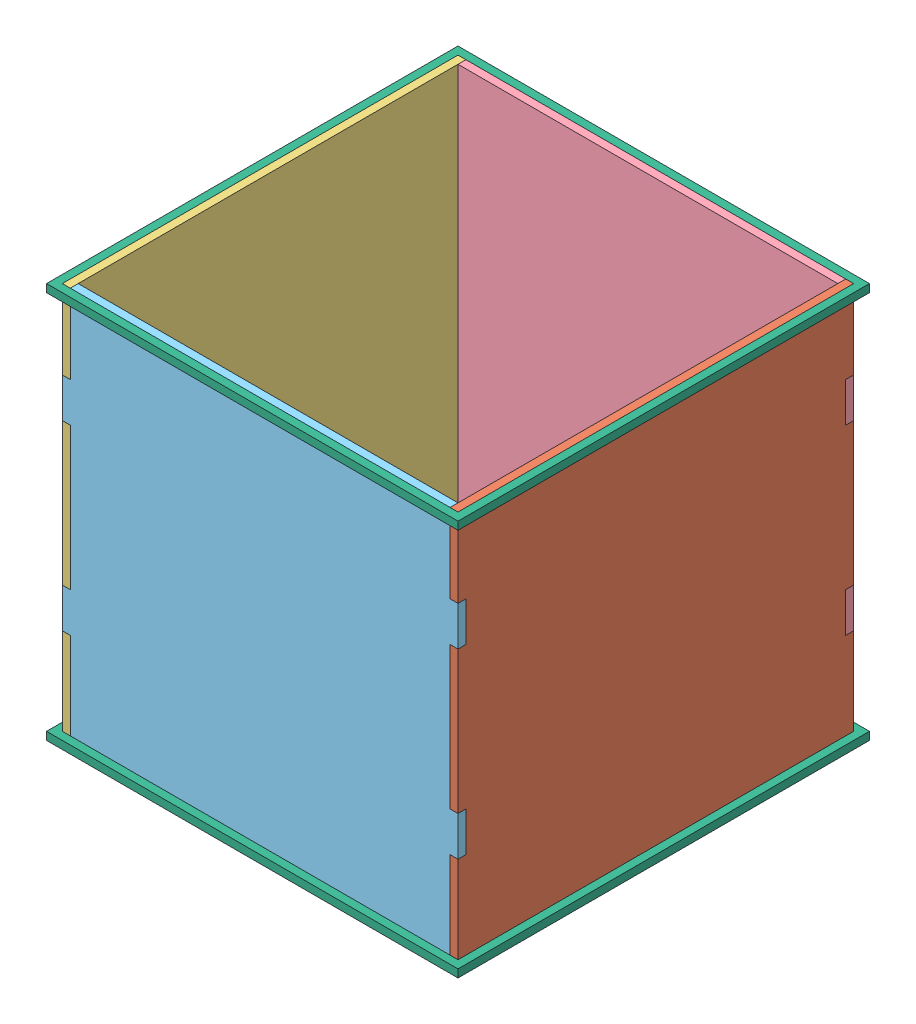
SolidWorks assembly cubeBox, configuration Default. Lengths in mm.
Overall size (104 100 104).
11 component instances, 10 part files, 38 mates.
Components (placement in the parent):
- base-3: base [Default] at origin size (100 2 100)
- side1-1: side1 [Default] at (0 2 0) x (1 0 0) z (0 1 0) size (2 100 100)
- side2-1: side2 [Default] at (0 2 0) x (1 0 0) z (0 1 0) size (2 100 100)
- side3-1: side3 [Default] at (0 2 0) x (1 0 0) z (0 1 0) size (100 2 100)
- side4-1: side4 [Default] at (0 2 0) x (1 0 0) z (0 1 0) size (100 2 100)
- Part6-1: Part6 [Default] at (0 2 0) x (0 -1 0) z (1 0 0)
- Part7-1: Part7 [Default] x (-1 0 0) z (0 -1 0)
- Part8-1: Part8 [Default] x (-1 0 0) z (0 -1 0)
- Part9-1: Part9 [Default] x (-1 0 0) z (0 -1 0)
- ringBase-2: ringBase [Default] at origin size (104 2 104)
- ringBase-3: ringBase [Default] at (0 98 0) size (104 2 104)
Mates (geometry in assembly coordinates):
- InPlace1: in place: plane of ? through (0 2 0) normal (0 1 0); plane of ? through (0 2 0) normal (0 1 0); moOrthogonalPlaneRef_w of ? through (0 2 0) normal (0 1 0); plane of ? through (0 2 0) normal (0 0 -1); plane of ? through (0 2 0) normal (0 1 0); line of ? through (-55 0 2) axis (0 1 0); plane of ? through (0 2 0) normal (0 1 0); unknown of ?
- Coincident1: coincident aligned: plane of base-3; plane of side1-1
- Coincident2: coincident aligned: moOrthogonalPlaneRef_w of base-3 through (0 2 0) normal (0 0 -1); plane of side1-1 through (0 2 0) normal (0 0 -1)
- Coincident3: coincident anti-aligned: moOrthogonalPlaneRef_w of base-3 through (0 2 0) normal (-1 0 0); plane of side1-1
- InPlace2: in place: plane of ? through (0 2 0) normal (0 1 0); plane of ? through (0 2 0) normal (0 1 0); plane of ? through (0 2 0) normal (0 1 0); plane of ? through (0 2 0) normal (0 0 -1); plane of ? through (0 2 0) normal (0 1 0); line of ? through (-55 0 2) axis (0 1 0); plane of ? through (0 2 0) normal (0 1 0); unknown of ?
- Coincident4: coincident aligned: plane of base-3; plane of side2-1
- Coincident5: coincident aligned: moOrthogonalPlaneRef_w of base-3 through (0 2 0) normal (0 0 -1); plane of side2-1 through (0 2 0) normal (0 0 -1)
- Coincident6: coincident anti-aligned: moOrthogonalPlaneRef_w of base-3 through (0 2 0) normal (-1 0 0); plane of side2-1
- InPlace3: in place: plane of ? through (0 2 0) normal (0 1 0); plane of ? through (0 2 0) normal (0 1 0); plane of ? through (0 2 0) normal (0 1 0); plane of ? through (0 2 0) normal (0 0 -1); plane of ? through (0 2 0) normal (0 1 0); line of ? through (-55 0 2) axis (0 1 0); plane of ? through (0 2 0) normal (0 1 0); unknown of ?
- Coincident7: coincident aligned: plane of base-3; plane of side3-1
- Coincident8: coincident aligned: moOrthogonalPlaneRef_w of base-3 through (0 2 0) normal (0 0 -1); plane of side3-1 through (0 2 0) normal (0 0 -1)
- Coincident9: coincident anti-aligned: moOrthogonalPlaneRef_w of base-3 through (0 2 0) normal (-1 0 0); plane of side3-1
- InPlace4: in place: plane of ? through (0 2 0) normal (0 1 0); plane of ? through (0 2 0) normal (0 1 0); plane of ? through (0 2 0) normal (0 1 0); plane of ? through (0 2 0) normal (0 0 -1); plane of ? through (0 2 0) normal (0 1 0); line of ? through (-55 0 2) axis (0 1 0); plane of ? through (0 2 0) normal (0 1 0); unknown of ?
- Coincident10: coincident aligned: plane of base-3; plane of side4-1
- Coincident11: coincident aligned: moOrthogonalPlaneRef_w of base-3 through (0 2 0) normal (0 0 -1); plane of side4-1 through (0 2 0) normal (0 0 -1)
- Coincident12: coincident anti-aligned: moOrthogonalPlaneRef_w of base-3 through (0 2 0) normal (-1 0 0); plane of side4-1
- InPlace6: in place: line of ? through (-1.1 0 2) axis (0 1 0); plane of Part6-1 through (0 2 0) normal (1 0 0); line of ? through (-1.1 0 2) axis (0 1 0); line of Part6-1 through (2 0 0) axis (0 -1 0); line of ? through (-1.1 0 2) axis (0 1 0); line of Part6-1 through (-55 0 2) axis (0 0 -1); line of ? through (-1.1 0 2) axis (0 1 0); unknown of Part6-1
- Coincident16: coincident aligned: plane of side4-1; plane of Part6-1
- Coincident17: coincident aligned: moOrthogonalPlaneRef_w of side4-1 through (2 0 0) axis (0 -1 0); plane of Part6-1
- Coincident18: coincident anti-aligned: moOrthogonalPlaneRef_w of side4-1 through (0 2 0) normal (0 1 0); plane of Part6-1
- InPlace7: in place: plane of ? through (0 0 0) normal (0 -1 0); plane of ? through (0 0 0) normal (0 -1 0); plane of ? through (0 0 0) normal (0 -1 0); unknown of ?; plane of ? through (0 0 0) normal (0 -1 0); line of ? through (55 -55 0) axis (0 0 -1); plane of ? through (0 0 0) normal (0 -1 0); unknown of ?
- Coincident19: coincident aligned: plane of base-3; plane of Part7-1
- Coincident20: coincident aligned: moOrthogonalPlaneRef_w of base-3 through (0 0 0) normal (0 0 -1); plane of Part7-1
- Coincident21: coincident anti-aligned: moOrthogonalPlaneRef_w of base-3 through (0 0 0) normal (1 0 0); plane of Part7-1
- InPlace8: in place: plane of ? through (0 0 0) normal (0 -1 0); plane of ? through (0 0 0) normal (0 -1 0); plane of ? through (0 0 0) normal (0 -1 0); unknown of ?; plane of ? through (0 0 0) normal (0 -1 0); line of ? through (55 -55 0) axis (0 0 -1); plane of ? through (0 0 0) normal (0 -1 0); unknown of ?
- Coincident22: coincident aligned: plane of base-3; plane of Part8-1
- Coincident23: coincident aligned: moOrthogonalPlaneRef_w of base-3 through (0 0 0) normal (0 0 -1); plane of Part8-1
- Coincident24: coincident anti-aligned: moOrthogonalPlaneRef_w of base-3 through (0 0 0) normal (1 0 0); plane of Part8-1
- InPlace9: in place: plane of ? through (0 0 0) normal (0 -1 0); plane of ? through (0 0 0) normal (0 -1 0); plane of ? through (0 0 0) normal (0 -1 0); unknown of ?; plane of ? through (0 0 0) normal (0 -1 0); line of ? through (55 -55 0) axis (0 0 -1); plane of ? through (0 0 0) normal (0 -1 0); unknown of ?
- Coincident25: coincident aligned: plane of base-3; plane of Part9-1
- Coincident26: coincident aligned: moOrthogonalPlaneRef_w of base-3 through (0 0 0) normal (0 0 -1); plane of Part9-1
- Coincident27: coincident anti-aligned: moOrthogonalPlaneRef_w of base-3 through (0 0 0) normal (1 0 0); plane of Part9-1
- Coincident30: coincident aligned: plane of base-3 through (0 0 0) normal (0 -1 0); plane of ringBase-2 through (0 0 0) normal (0 -1 0)
- Coincident31: coincident anti-aligned: plane of base-3 through (-50 2 -50) normal (-1 0 0); plane of ringBase-2 through (-50 2 -50) normal (1 0 0)
- Coincident32: coincident anti-aligned: plane of base-3 through (-50 2 50) normal (0 0 1); plane of ringBase-2 through (-50 2 50) normal (0 0 -1)
- Coincident36: coincident aligned: plane of side4-1 through (0 100 0) normal (0 1 0); plane of ringBase-3 through (0 100 0) normal (0 1 0)
- Coincident37: coincident anti-aligned: plane of side1-1 through (50 100 -50) normal (1 0 0); plane of ringBase-3 through (50 100 -50) normal (-1 0 0)
- Coincident38: coincident anti-aligned: plane of side4-1 through (-48 196.0208 50) normal (0 0 1); plane of ringBase-3 through (-50 100 50) normal (0 0 -1)
